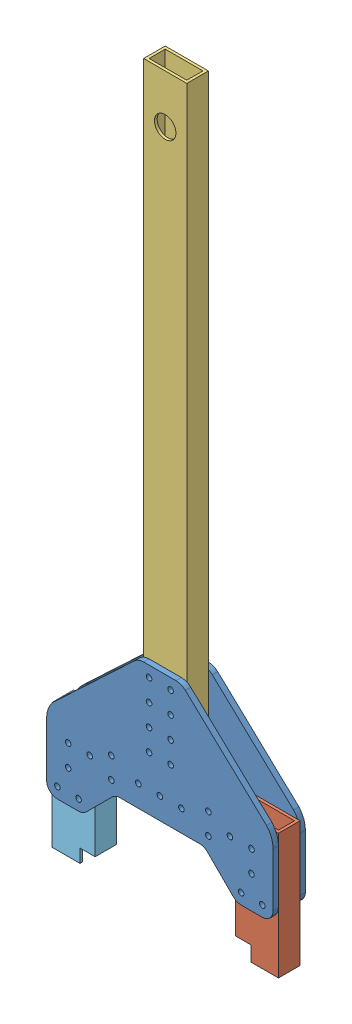
SolidWorks assembly Climber_v2, configuration Default. Lengths in mm.
Overall size (266.7 858.35 38.1).
7 component instances, 5 part files, 0 mates.
Components (placement in the parent):
- Climber_v2.step-1: Climber_v2.step [Default] at (936.2288 147.6953 -594.3772) size (266.7 858.35 38.1)
  - Part 4.step-1: Part 4.step [Default] at (-48.2589 45.3229 -21.4127) size (266.7 190.5 6.35)
  - Part 2.step-1: Part 2.step [Default] at (-48.2589 45.3229 -21.4127) size (50.8 147.64 25.4)
  - Part 1.step-1: Part 1.step [Default] at (59.6911 44.8366 -21.4127) x (1 0 0) z (0 1 0) size (50.8 25.4 711.2)
  - Part 4.step-2: Part 4.step [Default] at (-48.2589 45.3229 -53.1627) size (266.7 190.5 6.35)
  - Part 3.step-1: Part 3.step [Default] at (-48.2589 45.3229 -21.4127) size (165.1 50.8 25.4)
  - Part 1-0.step-1: Part 1-0.step [Default] at (-48.2589 45.3229 -21.4127) size (50.8 147.64 25.4)
